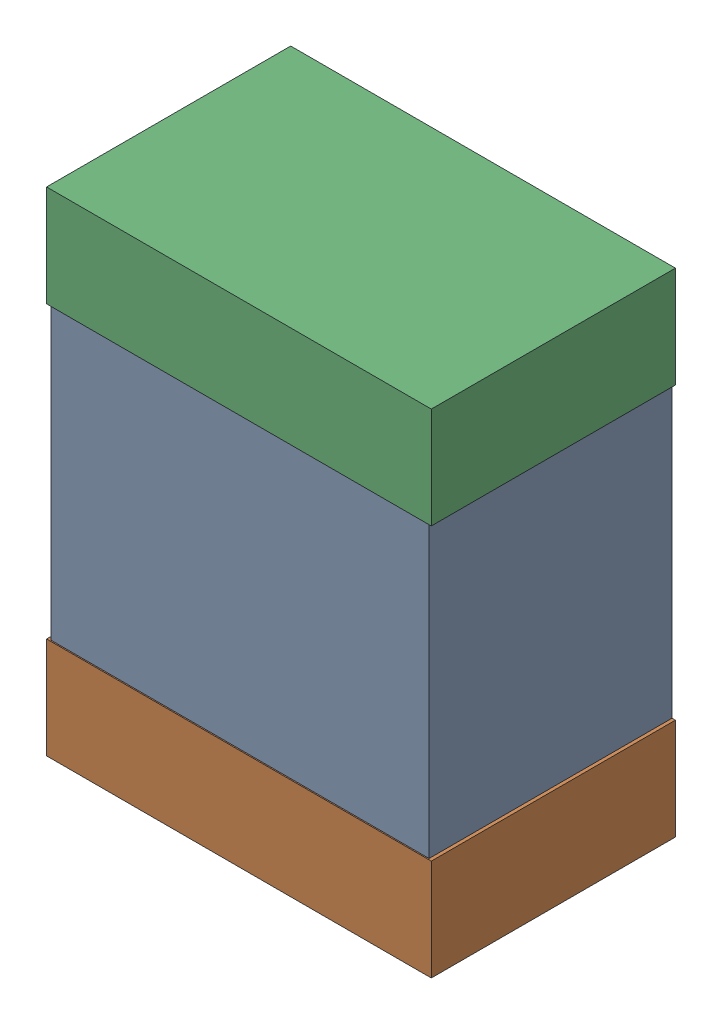
SolidWorks assembly R1Kanaloa_v2.0.0_Motor, configuration Default. Lengths in mm.
Overall size (2.85 3.65 1.81).
6 component instances, 2 part files, 0 mates.
Components (placement in the parent):
- 334789424-1: 334789424 [Default] at (107.188 107.696 0) size (2.8 3.6 1.8)
  - Extruded_10-1: Extruded_10 [Default] at origin size (2.8 3.6 1.8)
- 334789552-1: 334789552 [Default] at (107.188 106.246 0) size (2.85 0.75 1.81)
  - Extruded_9-1: Extruded_9 [Default] at origin size (2.85 0.75 1.81)
- 334789552-2: 334789552 [Default] at (107.188 109.146 0) size (2.85 0.75 1.81)
  - Extruded_9-1: Extruded_9 [Default] at origin size (2.85 0.75 1.81)
